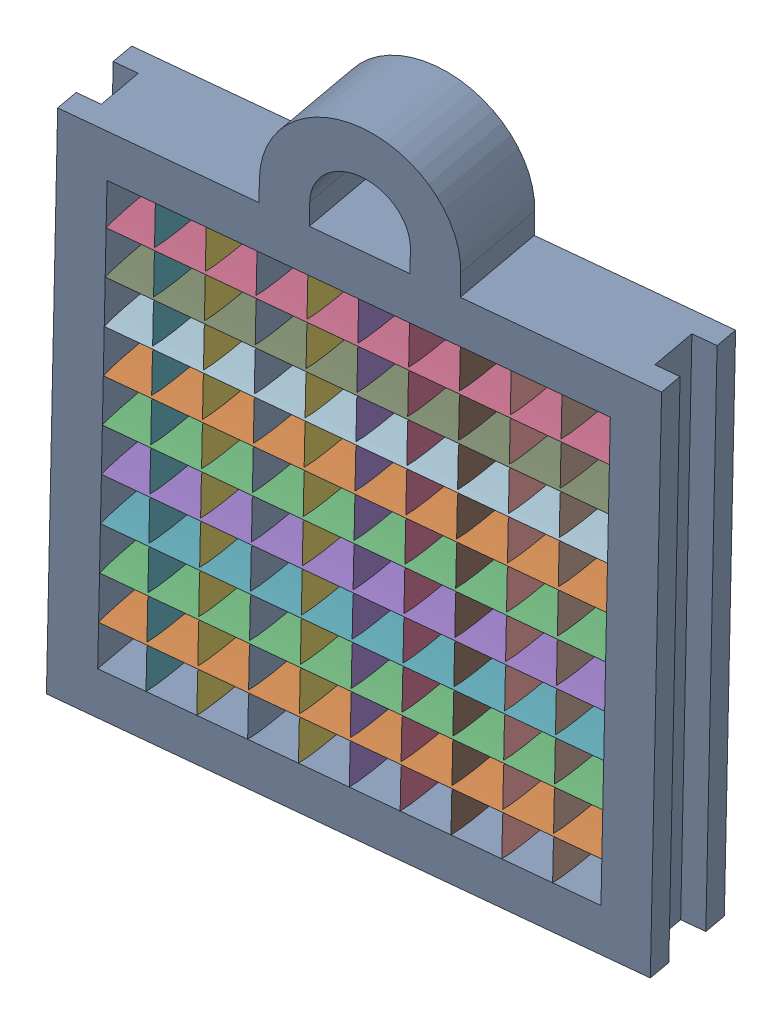
SolidWorks assembly Blade_assembly-1, configuration Default. Lengths in mm.
Overall size (128.96 151.07 42.39).
19 component instances, 2 part files, 0 mates.
Components (placement in the parent):
- Blade Frame-1-1: Blade Frame-1 [Default] at (771.0253 -161.3106 -497.9575) x (-0.987316 0.046404 0.151832) z (-0.150148 0.037854 -0.987939) size (120 145 20)
- Blade Piece-1-1: Blade Piece-1 [Default] at (675.3634 -97.277 -480.9651) x (0.051592 0.998205 0.030407) z (-0.150148 0.037854 -0.987939) size (1 100 20)
- Blade Piece-1-2: Blade Piece-1 [Default] at (674.8423 -107.3589 -481.2722) x (0.051592 0.998205 0.030407) z (-0.150148 0.037854 -0.987939) size (1 100 20)
- Blade Piece-1-3: Blade Piece-1 [Default] at (676.9266 -67.0314 -480.0438) x (0.051592 0.998205 0.030407) z (-0.150148 0.037854 -0.987939) size (1 100 20)
- Blade Piece-1-4: Blade Piece-1 [Default] at (674.3212 -117.4408 -481.5793) x (0.051592 0.998205 0.030407) z (-0.150148 0.037854 -0.987939) size (1 100 20)
- Blade Piece-1-5: Blade Piece-1 [Default] at (691.2502 -157.5612 -485.6895) x (0.987316 -0.046404 -0.151832) z (0.150148 -0.037854 0.987939) size (1 100 20)
- Blade Piece-1-6: Blade Piece-1 [Default] at (681.2783 -157.0925 -484.156) x (0.987316 -0.046404 -0.151832) z (0.150148 -0.037854 0.987939) size (1 100 20)
- Blade Piece-1-7: Blade Piece-1 [Default] at (761.0534 -160.8419 -496.424) x (0.987316 -0.046404 -0.151832) z (0.150148 -0.037854 0.987939) size (1 100 20)
- Blade Piece-1-8: Blade Piece-1 [Default] at (676.4055 -77.1133 -480.3509) x (0.051592 0.998205 0.030407) z (-0.150148 0.037854 -0.987939) size (1 100 20)
- Blade Piece-1-9: Blade Piece-1 [Default] at (751.0815 -160.3733 -494.8905) x (0.987316 -0.046404 -0.151832) z (0.150148 -0.037854 0.987939) size (1 100 20)
- Blade Piece-1-10: Blade Piece-1 [Default] at (741.1096 -159.9046 -493.357) x (0.987316 -0.046404 -0.151832) z (0.150148 -0.037854 0.987939) size (1 100 20)
- Blade Piece-1-11: Blade Piece-1 [Default] at (675.8845 -87.1952 -480.658) x (0.051592 0.998205 0.030407) z (-0.150148 0.037854 -0.987939) size (1 100 20)
- Blade Piece-1-12: Blade Piece-1 [Default] at (701.2221 -158.0299 -487.223) x (0.987316 -0.046404 -0.151832) z (0.150148 -0.037854 0.987939) size (1 100 20)
- Blade Piece-1-13: Blade Piece-1 [Default] at (672.758 -147.6864 -482.5007) x (0.051592 0.998205 0.030407) z (-0.150148 0.037854 -0.987939) size (1 100 20)
- Blade Piece-1-14: Blade Piece-1 [Default] at (673.2791 -137.6045 -482.1935) x (0.051592 0.998205 0.030407) z (-0.150148 0.037854 -0.987939) size (1 100 20)
- Blade Piece-1-15: Blade Piece-1 [Default] at (731.1377 -159.4359 -491.8235) x (0.987316 -0.046404 -0.151832) z (0.150148 -0.037854 0.987939) size (1 100 20)
- Blade Piece-1-16: Blade Piece-1 [Default] at (721.1658 -158.9672 -490.29) x (0.987316 -0.046404 -0.151832) z (0.150148 -0.037854 0.987939) size (1 100 20)
- Blade Piece-1-17: Blade Piece-1 [Default] at (711.1939 -158.4986 -488.7565) x (0.987316 -0.046404 -0.151832) z (0.150148 -0.037854 0.987939) size (1 100 20)
- Blade Piece-1-18: Blade Piece-1 [Default] at (673.8002 -127.5226 -481.8864) x (0.051592 0.998205 0.030407) z (-0.150148 0.037854 -0.987939) size (1 100 20)
